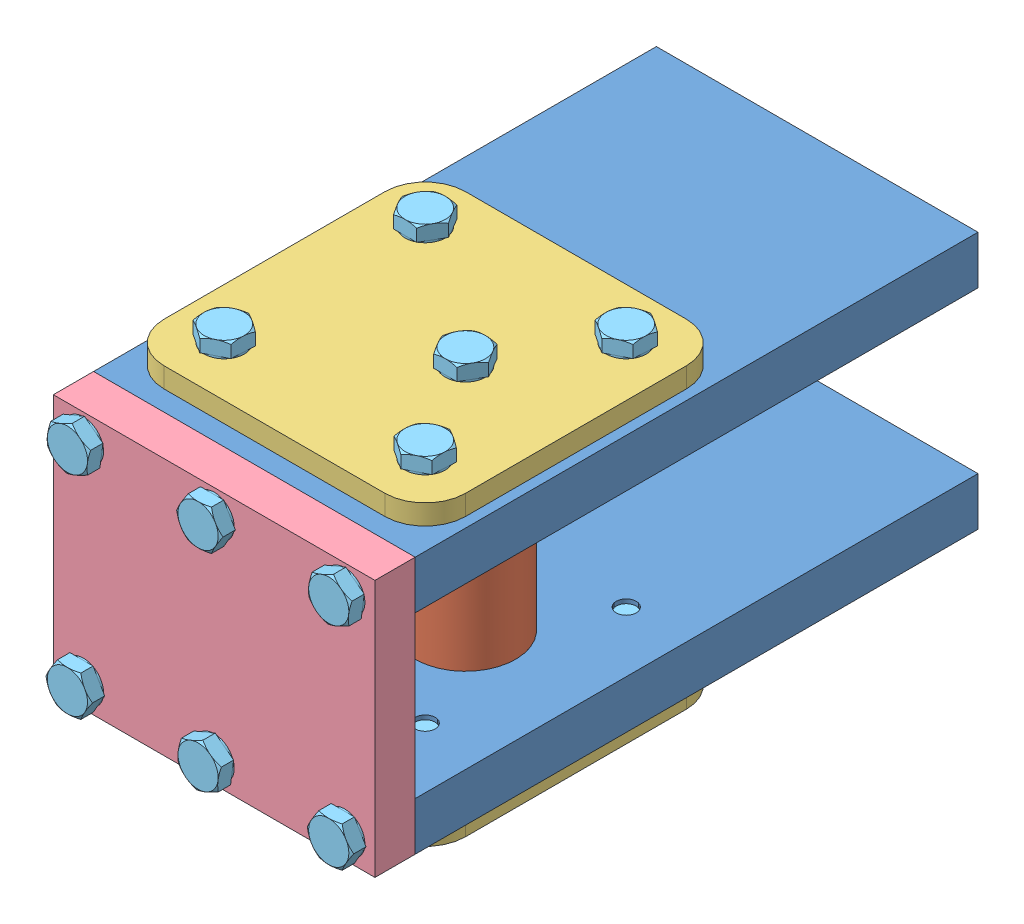
SolidWorks assembly 010300_cylinder_mount, configuration Default. Lengths in mm.
Overall size (80 82 154).
22 component instances, 5 part files, 49 mates.
Components (placement in the parent):
- 010301_cylinder_mount_front-1: 010301_cylinder_mount_front [Default] at (0 -26 0) size (80 12 140)
- 010301_cylinder_mount_front-2: 010301_cylinder_mount_front [Default] at (0 26 0) size (80 12 140)
- 010302_cylinder_mount_pin-1: 010302_cylinder_mount_pin [Default] at (10 0 -42.5) x (0.998607 0 0.052773) z (0 -1 0) size (25 25 64)
- 010303_cylinder_mount_pincover-1: 010303_cylinder_mount_pincover [Default] at (0 32 -42.5) x (1 0 0) z (0 1 0) size (75 75 5)
- 010303_cylinder_mount_pincover-2: 010303_cylinder_mount_pincover [Default] at (0 -32 -42.5) x (1 0 0) z (0 -1 0) size (75 75 5)
- 010304_cylinder_mount_bottom-1: 010304_cylinder_mount_bottom [Default] at (-40 0 0) size (80 64 10)
- hex screw gradeab_iso-1: hex screw gradeab_iso [ISO 4017 - M6 x 16-N] at (-25 41 -67.5) x (0 -1 0) z (0 0 -1) size (20 11.55 10)
- hex screw gradeab_iso-2: hex screw gradeab_iso [ISO 4017 - M6 x 16-N] at (25 41 -67.5) x (0 -1 0) z (-0.546944 0 0.837169) size (20 11.55 10)
- hex screw gradeab_iso-3: hex screw gradeab_iso [ISO 4017 - M6 x 16-N] at (10 41 -42.5) x (0 -1 0) z (0 0 -1) size (20 11.55 10)
- hex screw gradeab_iso-4: hex screw gradeab_iso [ISO 4017 - M6 x 16-N] at (-25 41 -17.5) x (0 -1 0) z (-0.546944 0 0.837169) size (20 11.55 10)
- hex screw gradeab_iso-5: hex screw gradeab_iso [ISO 4017 - M6 x 16-N] at (25 41 -17.5) x (0 -1 0) z (-0.546944 0 0.837169) size (20 11.55 10)
- hex screw gradeab_iso-6: hex screw gradeab_iso [ISO 4017 - M6 x 16-N] at (-25 -41 -67.5) x (0 1 0) z (-0.546944 0 -0.837169) size (20 11.55 10)
- hex screw gradeab_iso-7: hex screw gradeab_iso [ISO 4017 - M6 x 16-N] at (25 -41 -67.5) x (0 1 0) z (-0.546944 0 -0.837169) size (20 11.55 10)
- hex screw gradeab_iso-8: hex screw gradeab_iso [ISO 4017 - M6 x 16-N] at (10 -41 -42.5) x (0 1 0) z (-0.546944 0 -0.837169) size (20 11.55 10)
- hex screw gradeab_iso-9: hex screw gradeab_iso [ISO 4017 - M6 x 16-N] at (-25 -41 -17.5) x (0 1 0) z (0 0 1) size (20 11.55 10)
- hex screw gradeab_iso-10: hex screw gradeab_iso [ISO 4017 - M6 x 16-N] at (25 -41 -17.5) x (0 1 0) z (0 0 1) size (20 11.55 10)
- hex screw gradeab_iso-11: hex screw gradeab_iso [ISO 4017 - M6 x 16-N] at (-32.5 26 14) x (0 0 -1) z (0.383049 -0.923728 0) size (20 11.55 10)
- hex screw gradeab_iso-12: hex screw gradeab_iso [ISO 4017 - M6 x 16-N] at (0 26 14) x (0 0 -1) z (0 1 0) size (20 11.55 10)
- hex screw gradeab_iso-13: hex screw gradeab_iso [ISO 4017 - M6 x 16-N] at (0 -26 14) x (0 0 -1) z (0.383049 -0.923728 0) size (20 11.55 10)
- hex screw gradeab_iso-14: hex screw gradeab_iso [ISO 4017 - M6 x 16-N] at (32.5 -26 14) x (0 0 -1) z (0 1 0) size (20 11.55 10)
- hex screw gradeab_iso-15: hex screw gradeab_iso [ISO 4017 - M6 x 16-N] at (-32.5 -26 14) x (0 0 -1) z (0 1 0) size (20 11.55 10)
- hex screw gradeab_iso-16: hex screw gradeab_iso [ISO 4017 - M6 x 16-N] at (32.5 26 14) x (0 0 -1) z (0.383049 -0.923728 0) size (20 11.55 10)
Mates (geometry in assembly coordinates):
- Coincident1: coincident aligned: plane of Cylinderfixture_front-1 through (0 -26 0) normal (0 0 1)
- Coincident3: coincident aligned: plane of Cylinderfixture_front-1 through (0 -26 0) normal (1 0 0)
- Concentric1: concentric anti-aligned: cylinder of Cylinderfixture_front-2 through (10 32 -42.5) axis (0 -1 0) radius 12.5; cylinder of Cylinderficture_pin-1 through (10 -32 -42.5) axis (0 1 0) radius 12.5
- Coincident13: coincident aligned: plane of Cylinderfixture_front-2 through (0 32 0) normal (0 1 0); plane of Cylinderficture_pin-1 through (10 32 -42.5) normal (0 1 0)
- Concentric2: concentric anti-aligned: cylinder of Cylinderfixture_front-1 through (10 -20 -42.5) axis (0 -1 0) radius 12.5; cylinder of Cylinderficture_pin-1 through (10 -32 -42.5) axis (0 1 0) radius 12.5
- Coincident17: coincident aligned: plane of Cylinderfixture_front-1 through (0 -32 0) normal (0 -1 0); plane of Cylinderficture_pin-1 through (10 -32 -42.5) normal (0 -1 0)
- Coincident18: coincident anti-aligned: plane of Cylinderficture_pin-1 through (10 0 -42.5) normal (0 -1 0)
- Coincident20: coincident aligned: plane of Cylinderfixture_front-1 through (-40 -20 -140) normal (-1 0 0); plane of Cylinderfixture_front-2 through (-40 32 -140) normal (-1 0 0)
- Coincident23: coincident anti-aligned: plane of Cylinderfixture_front-2 through (0 32 0) normal (0 1 0); plane of Cylinderfixture_pincover-1 through (0 32 -42.5) normal (0 -1 0)
- Concentric5: concentric aligned: cylinder of Cylinderfixture_front-2 through (25 32 -67.5) axis (0 1 0) radius 2.5; circle of Cylinderfixture_pincover-1
- Concentric6: concentric aligned: cylinder of Cylinderfixture_front-2 through (25 32 -17.5) axis (0 1 0) radius 2.5; cylinder of Cylinderfixture_pincover-1 through (25 37 -17.5) axis (0 1 0) radius 3.5
- Coincident24: coincident anti-aligned: plane of Cylinderfixture_front-1 through (0 -32 0) normal (0 -1 0); plane of Cylinderfixture_pincover-2 through (0 -32 -42.5) normal (0 1 0)
- Concentric7: concentric anti-aligned: cylinder of Cylinderfixture_front-1 through (25 -20 -67.5) axis (0 1 0) radius 2.5; cylinder of Cylinderfixture_pincover-2 through (25 -37 -67.5) axis (0 -1 0) radius 3.5
- Concentric8: concentric anti-aligned: cylinder of Cylinderfixture_front-1 through (25 -20 -17.5) axis (0 1 0) radius 2.5; cylinder of Cylinderfixture_pincover-2 through (25 -37 -17.5) axis (0 -1 0) radius 3.5
- Concentric9: concentric aligned: cylinder of Cylinderfixture_pincover-1 through (-25 37 -67.5) axis (0 1 0) radius 3.5; cylinder of hex screw gradeab_iso-1 through (-25 41 -67.5) axis (0 1 0) radius 3
- Concentric10: concentric aligned: cylinder of Cylinderfixture_pincover-1 through (25 37 -67.5) axis (0 1 0) radius 3.5; cylinder of hex screw gradeab_iso-2 through (25 41 -67.5) axis (0 1 0) radius 3
- Concentric11: concentric aligned: cylinder of Cylinderfixture_pincover-1 through (10 37 -42.5) axis (0 1 0) radius 3.5; cylinder of hex screw gradeab_iso-3 through (10 41 -42.5) axis (0 1 0) radius 3
- Concentric12: concentric aligned: cylinder of Cylinderfixture_pincover-1 through (-25 37 -17.5) axis (0 1 0) radius 3.5; cylinder of hex screw gradeab_iso-4 through (-25 41 -17.5) axis (0 1 0) radius 3
- Concentric13: concentric aligned: cylinder of Cylinderfixture_pincover-1 through (25 37 -17.5) axis (0 1 0) radius 3.5; cylinder of hex screw gradeab_iso-5 through (25 41 -17.5) axis (0 1 0) radius 3
- Coincident25: coincident anti-aligned: plane of Cylinderfixture_pincover-1 through (0 37 -42.5) normal (0 1 0); plane of hex screw gradeab_iso-3 through (4.2265 37 -42.5) normal (0 -1 0)
- Coincident26: coincident anti-aligned: plane of Cylinderfixture_pincover-1 through (0 37 -42.5) normal (0 1 0); plane of hex screw gradeab_iso-1 through (-30.7735 37 -67.5) normal (0 -1 0)
- Coincident27: coincident anti-aligned: plane of Cylinderfixture_pincover-1 through (0 37 -42.5) normal (0 1 0); plane of hex screw gradeab_iso-2 through (29.8334 37 -64.3422) normal (0 -1 0)
- Coincident28: coincident anti-aligned: plane of Cylinderfixture_pincover-1 through (0 37 -42.5) normal (0 1 0); plane of hex screw gradeab_iso-4 through (-20.1666 37 -14.3422) normal (0 -1 0)
- Coincident29: coincident anti-aligned: plane of Cylinderfixture_pincover-1 through (0 37 -42.5) normal (0 1 0); plane of hex screw gradeab_iso-5 through (29.8334 37 -14.3422) normal (0 -1 0)
- Concentric14: concentric aligned: cylinder of Cylinderfixture_pincover-2 through (25 -37 -67.5) axis (0 -1 0) radius 3.5; cylinder of hex screw gradeab_iso-7 through (25 -41 -67.5) axis (0 -1 0) radius 3
- Concentric15: concentric aligned: cylinder of Cylinderfixture_pincover-2 through (-25 -37 -67.5) axis (0 -1 0) radius 3.5; cylinder of hex screw gradeab_iso-6 through (-25 -41 -67.5) axis (0 -1 0) radius 3
- Concentric16: concentric aligned: cylinder of Cylinderfixture_pincover-2 through (10 -37 -42.5) axis (0 -1 0) radius 3.5; cylinder of hex screw gradeab_iso-8 through (10 -41 -42.5) axis (0 -1 0) radius 3
- Concentric17: concentric aligned: cylinder of Cylinderfixture_pincover-2 through (-25 -37 -17.5) axis (0 -1 0) radius 3.5; cylinder of hex screw gradeab_iso-9 through (-25 -41 -17.5) axis (0 -1 0) radius 3
- Concentric18: concentric aligned: cylinder of Cylinderfixture_pincover-2 through (25 -37 -17.5) axis (0 -1 0) radius 3.5; cylinder of hex screw gradeab_iso-10 through (25 -41 -17.5) axis (0 -1 0) radius 3
- Coincident31: coincident anti-aligned: plane of Cylinderfixture_pincover-2 through (0 -37 -42.5) normal (0 -1 0); plane of hex screw gradeab_iso-6 through (-20.1666 -37 -70.6578) normal (0 1 0)
- Coincident32: coincident anti-aligned: plane of Cylinderfixture_pincover-2 through (0 -37 -42.5) normal (0 -1 0); plane of hex screw gradeab_iso-7 through (29.8334 -37 -70.6578) normal (0 1 0)
- Coincident33: coincident anti-aligned: plane of Cylinderfixture_pincover-2 through (0 -37 -42.5) normal (0 -1 0); plane of hex screw gradeab_iso-8 through (14.8334 -37 -45.6578) normal (0 1 0)
- Coincident34: coincident anti-aligned: plane of Cylinderfixture_pincover-2 through (0 -37 -42.5) normal (0 -1 0); plane of hex screw gradeab_iso-9 through (-30.7735 -37 -17.5) normal (0 1 0)
- Coincident35: coincident anti-aligned: plane of Cylinderfixture_pincover-2 through (0 -37 -42.5) normal (0 -1 0); plane of hex screw gradeab_iso-10 through (19.2265 -37 -17.5) normal (0 1 0)
- Coincident36: coincident anti-aligned: plane of Cylinderfixture_front-2 through (-40 32 0) normal (0 0 1); plane of Cylinderficture_bottom-1 through (-40 0 0) normal (0 0 -1)
- Coincident37: coincident aligned: plane of Cylinderfixture_front-2 through (0 32 0) normal (0 1 0); plane of Cylinderficture_bottom-1 through (-40 32 10) normal (0 1 0)
- Coincident38: coincident aligned: plane of Cylinderfixture_front-2 through (40 32 -140) normal (1 0 0); plane of Cylinderficture_bottom-1 through (40 32 10) normal (1 0 0)
- Concentric19: concentric aligned: cylinder of Cylinderficture_bottom-1 through (-32.5 26 10) axis (0 0 1) radius 3.5; cylinder of hex screw gradeab_iso-11 through (-32.5 26 14) axis (0 0 1) radius 3
- Concentric20: concentric aligned: cylinder of Cylinderficture_bottom-1 through (0 26 10) axis (0 0 1) radius 3.5; cylinder of hex screw gradeab_iso-12 through (0 26 14) axis (0 0 1) radius 3
- Concentric21: concentric aligned: cylinder of Cylinderficture_bottom-1 through (32.5 26 10) axis (0 0 1) radius 3.5; cylinder of hex screw gradeab_iso-16 through (32.5 26 14) axis (0 0 1) radius 3
- Concentric22: concentric aligned: cylinder of Cylinderficture_bottom-1 through (-32.5 -26 10) axis (0 0 1) radius 3.5; cylinder of hex screw gradeab_iso-15 through (-32.5 -26 14) axis (0 0 1) radius 3
- Concentric23: concentric aligned: cylinder of Cylinderficture_bottom-1 through (0 -26 10) axis (0 0 1) radius 3.5; cylinder of hex screw gradeab_iso-13 through (0 -26 14) axis (0 0 1) radius 3
- Concentric24: concentric aligned: cylinder of Cylinderficture_bottom-1 through (32.5 -26 10) axis (0 0 1) radius 3.5; cylinder of hex screw gradeab_iso-14 through (32.5 -26 14) axis (0 0 1) radius 3
- Coincident39: coincident anti-aligned: plane of Cylinderficture_bottom-1 through (-40 0 10) normal (0 0 1); plane of hex screw gradeab_iso-15 through (-38.2735 -26 10) normal (0 0 -1)
- Coincident40: coincident anti-aligned: plane of Cylinderficture_bottom-1 through (-40 0 10) normal (0 0 1); plane of hex screw gradeab_iso-13 through (5.3331 -23.7885 10) normal (0 0 -1)
- Coincident41: coincident anti-aligned: plane of Cylinderficture_bottom-1 through (-40 0 10) normal (0 0 1); plane of hex screw gradeab_iso-14 through (26.7265 -26 10) normal (0 0 -1)
- Coincident42: coincident anti-aligned: plane of Cylinderficture_bottom-1 through (-40 0 10) normal (0 0 1); plane of hex screw gradeab_iso-11 through (-27.1669 28.2115 10) normal (0 0 -1)
- Coincident43: coincident anti-aligned: plane of Cylinderficture_bottom-1 through (-40 0 10) normal (0 0 1); plane of hex screw gradeab_iso-12 through (-5.7735 26 10) normal (0 0 -1)
- Coincident44: coincident anti-aligned: plane of Cylinderficture_bottom-1 through (-40 0 10) normal (0 0 1); plane of hex screw gradeab_iso-16 through (37.8331 28.2115 10) normal (0 0 -1)
